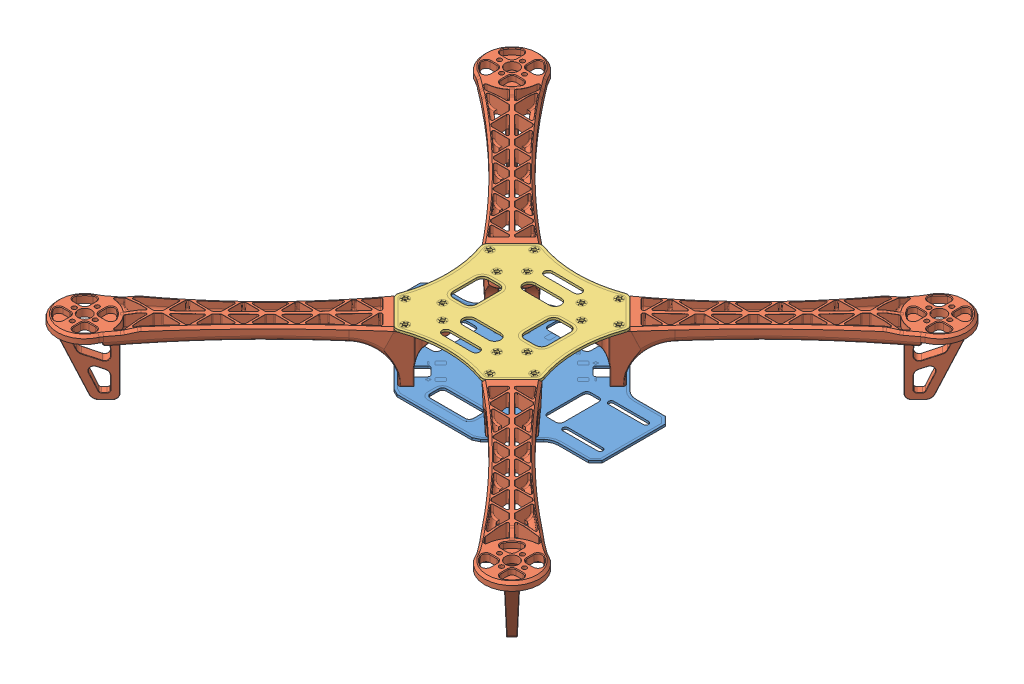
SolidWorks assembly Assembly, configuration Default. Lengths in mm.
Overall size (375.45 55.34 375.45).
6 component instances, 3 part files, 15 mates.
Components (placement in the parent):
- Base bottom-1: Base bottom [Default] at (67.5563 86.9564 146.6689) size (182 1.6 118)
- arm-1: arm [Default] at (165.9237 126.3564 245.0469) x (-0.707107 0 0.707107) z (-0.707107 0 -0.707107) size (40.75 55.34 213.92)
- arm-2: arm [Default] at (-30.8217 126.3564 245.0362) x (-0.707107 0 -0.707107) z (0.707107 0 -0.707107) size (40.75 55.34 213.92)
- arm-3: arm [Default] at (165.9344 126.3564 48.3015) x (0.707107 0 0.707107) z (-0.707107 0 0.707107) size (40.75 55.34 213.92)
- arm-4: arm [Default] at (-30.811 126.3564 48.2908) x (0.707107 0 -0.707107) z (0.707107 0 0.707107) size (40.75 55.34 213.92)
- Base Top-1: Base Top [Default] at (67.5563 125.3865 146.6689) x (0 0 -1) z (1 0 0) size (108.15 1.65 108.15)
Mates (geometry in assembly coordinates):
- Coincident2: coincident: plane of assembly; plane of assembly; plane of Base bottom-1 through (4.0563 87.7564 186.9169) normal (0 1 0); plane of arm-1 through (104.3913 87.7564 193.9796) normal (0 -1 0)
- Coincident3: coincident: line of assembly; line of assembly; axis of Base bottom-1 through (99.5883 86.1554 193.1965) axis (0 1 0); axis of arm-1 through (99.5883 92.7564 193.1965) axis (0 -1 0)
- Coincident4: coincident: line of assembly; line of assembly; axis of Base bottom-1 through (114.084 86.1554 178.7008) axis (0 1 0); axis of arm-1 through (114.084 92.7564 178.7008) axis (0 -1 0)
- Coincident5: coincident: plane of assembly; plane of assembly; plane of Base bottom-1 through (4.0563 87.7564 186.9169) normal (0 1 0); plane of arm-2 through (35.6249 87.7564 197.7501) normal (0 -1 0)
- Coincident6: coincident: line of assembly; line of assembly; axis of Base bottom-1 through (21.0287 86.1554 178.7008) axis (0 1 0); axis of arm-2 through (21.0287 92.7564 178.7008) axis (0 -1 0)
- Coincident7: coincident: line of assembly; line of assembly; axis of Base bottom-1 through (35.5244 86.1554 193.1965) axis (0 1 0); axis of arm-2 through (35.5244 92.7564 193.1965) axis (0 -1 0)
- Coincident8: coincident: line of assembly; line of assembly; axis of Base bottom-1 through (114.084 86.1554 114.6369) axis (0 1 0); axis of arm-3 through (114.084 92.7564 114.6369) axis (0 -1 0)
- Coincident9: coincident: plane of assembly; plane of assembly; plane of Base bottom-1 through (4.0563 87.7564 186.9169) normal (0 1 0); plane of arm-3 through (114.8671 87.7564 109.8339) normal (0 -1 0)
- Coincident10: coincident: line of assembly; line of assembly; axis of Base bottom-1 through (99.5883 86.1554 100.1412) axis (0 1 0); axis of arm-3 through (99.5883 92.7564 100.1412) axis (0 -1 0)
- Coincident13: coincident: line of assembly; line of assembly; axis of Base bottom-1 through (35.5244 86.1554 100.1412) axis (0 1 0); axis of arm-4 through (35.5244 92.7564 100.1412) axis (0 -1 0)
- Coincident14: coincident: plane of assembly; plane of assembly; plane of Base bottom-1 through (4.0563 87.7564 186.9169) normal (0 1 0); plane of arm-4 through (30.7214 87.7564 99.3581) normal (0 -1 0)
- Coincident15: coincident: line of assembly; line of assembly; axis of Base bottom-1 through (21.0287 86.1554 114.6369) axis (0 1 0); axis of arm-4 through (21.0287 92.7564 114.6369) axis (0 -1 0)
- Coincident16: coincident: plane of arm-1 through (121.2204 124.5615 177.999) normal (0 1 0); plane of ? through (-6.3522 124.5615 152.2407) normal (0 -1 0)
- Coincident17: coincident: line of assembly; line of assembly; axis of arm-1 through (99.0226 119.5615 194.7521) axis (0 1 0); axis of Base Top-1 through (99.0226 124.5605 194.7521) axis (0 1 0)
- Coincident18: coincident: line of assembly; line of assembly; axis of arm-1 through (115.6396 119.5615 178.1351) axis (0 1 0); axis of Base Top-1 through (115.6396 124.5605 178.1351) axis (0 1 0)
